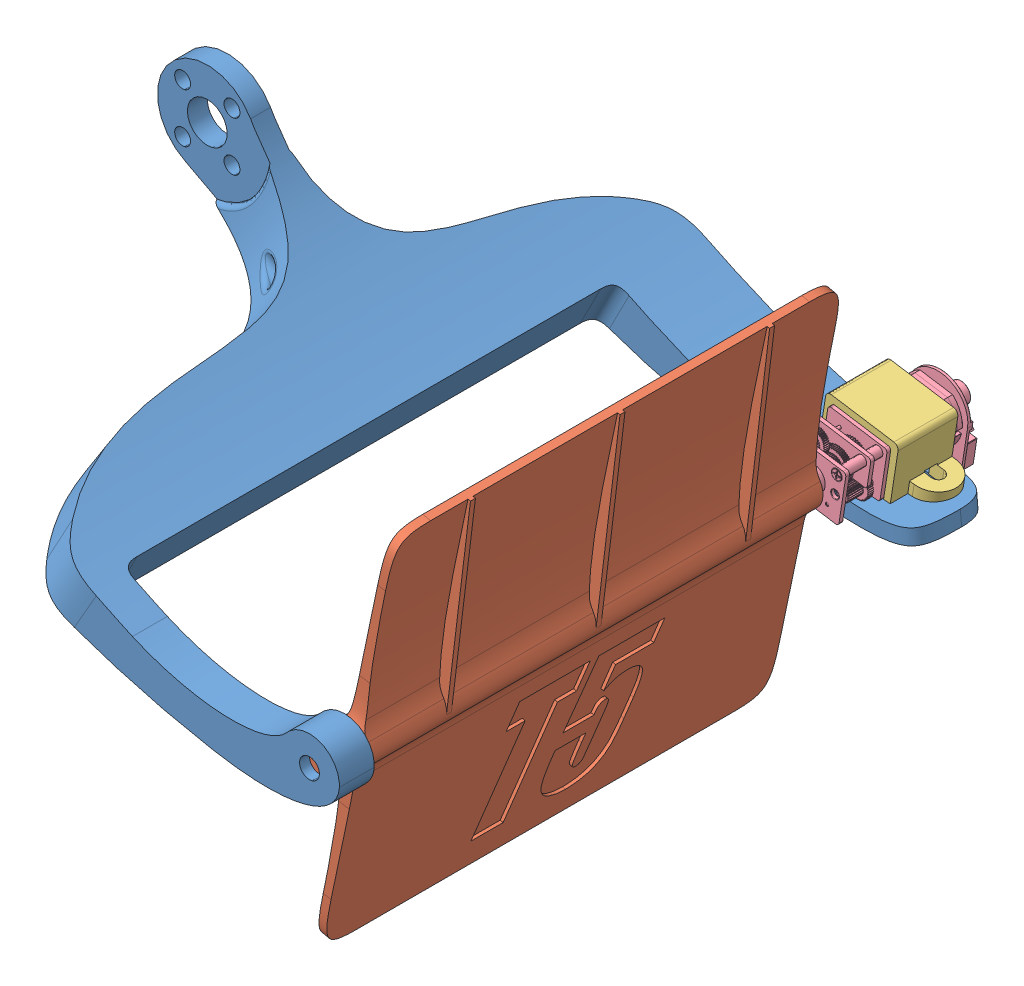
SolidWorks assembly 寒假-转轮+支架, configuration 默认. Lengths in mm.
Overall size (119.84 84.65 131.05).
5 component instances, 4 part files, 5 mates.
Components (placement in the parent):
- 寒假-支架-1: 寒假-支架 [默认] at origin size (114.34 52.98 125.66)
- 寒假-转轮-1: 寒假-转轮 [默认] at (89.4958 -32.9181 17) x (-0.978789 0.204873 0) z (0 0 -1) size (24.82 80.09 97.05)
- N20+支架-1: N20+支架 [默认] at (108.6049 -9.8919 -46.2748) x (-0.988115 0.153717 0) z (-0.153717 -0.988115 0) size (25 40 17.45)
  - 电机固定n20-1: 电机固定n20 [默认] at (15.3425 -1.3248 19.34) size (25 12 11.32)
  - JGA12-N20编码器DC马达[JGA12-N20-100K]-1: JGA12-N20编码器DC马达[JGA12-N20-100K] [JGA12-N20-100K] at (15.3425 7.6752 25.69) x (0 0 -1) z (0 1 0) size (17.2 12.2 40)
Mates (geometry in assembly coordinates):
- 重合1: coordinate: point of assembly; point of 寒假-支架-1; point of assembly
- 同心1: concentric: cylinder of assembly; cylinder of assembly; cylinder of 寒假-转轮-1 through (89.4958 -32.9181 -18) axis (0 0 -1) radius 1.5; cylinder of N20+支架-1/JGA12-N20编码器DC马达[JGA12-N20-100K]-1 through (89.4958 -32.9181 -29.95) axis (0 0 -1) radius 1.5
- 同心2: concentric: cylinder of assembly; cylinder of assembly; cylinder of 寒假-支架-1 through (89.4958 -32.9181 89.7744) axis (0 0 -1) radius 3.5; cylinder of 寒假-转轮-1 through (89.4958 -32.9181 69) axis (0 0 -1) radius 2
- 重合2: coincident: plane of assembly; plane of assembly; plane of 寒假-支架-1 through (44.9101 -23.4521 64) normal (0 0 -1); plane of 寒假-转轮-1 through (89.4958 -32.9181 64) normal (0 0 1)
- 重合3: coincident: plane of assembly; plane of assembly; plane of 寒假-支架-1 through (99.0558 -38.8094 -48) normal (0 0 1); plane of N20+支架-1/电机固定n20-1 through (95.1216 -35.787 -48) normal (0 0 1)
